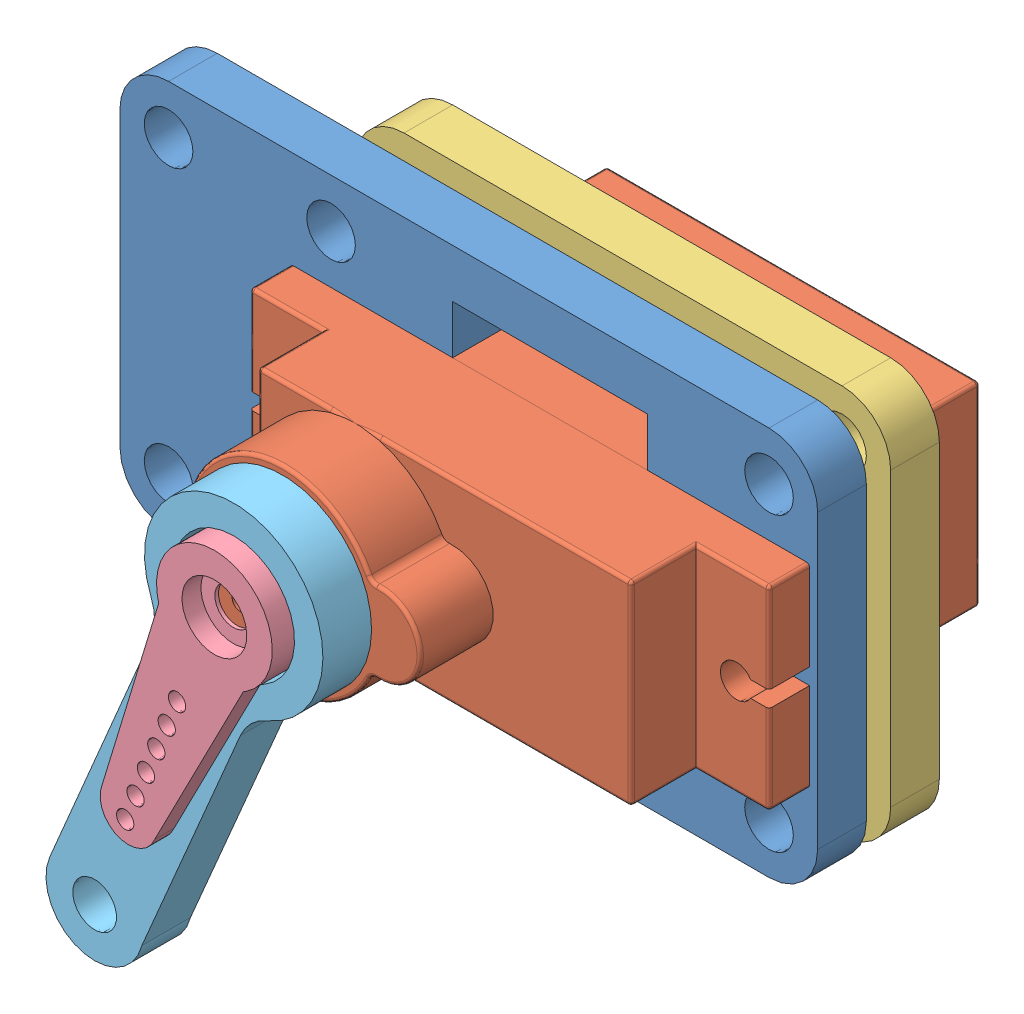
SolidWorks assembly Montagem2, configuration Valor predeterminado. Lengths in mm.
Overall size (43.02 37.14 30.2).
5 component instances, 5 part files, 10 mates.
Components (placement in the parent):
- 22-1: 22 [Défaut] at (-31.5156 48.4679 41.5162) size (43.02 24 3)
- Servo-1: Servo [Valor predeterminado] at (7.2328 7.1554 29.5162) x (1 0 0) z (0 -1 0) size (32 28.61 12)
- 21-1: 21 [Défaut] at (-21.7974 23.8068 37.0162) size (33 24 3)
- Helice-2: Helice [Default] at (18.3291 -0.913 62.5492) x (0.926593 -0.376065 0) z (0 0 1) size (7.14 19.41 4.19)
- 5-1: 5 [Défaut] at (-16.6615 -14.3676 55.5162) x (-0.390245 -0.920711 0) z (0 0 1) size (30.47 11 3)
Mates (geometry in assembly coordinates):
- Coincidente7: coincident anti-aligned: plane of 22-1 through (32.2328 10.1554 44.5162) normal (0 0 1); plane of Servo-1 through (7.2328 -4.8446 44.5162) normal (0 0 -1)
- Coincidente8: coincident anti-aligned: plane of 22-1 through (24.7328 7.1554 44.5162) normal (0 -1 0); plane of Servo-1 through (7.2328 7.1554 29.5162) normal (0 1 0)
- Concêntrico3: concentric aligned: circle of 22-1; circle of 21-1
- Concêntrico4: concentric aligned: circle of 22-1; circle of 21-1
- Coincidente11: coincident anti-aligned: plane of Servo-1 through (16.1182 -0.3402 55.5162) normal (0 0 1); plane of Helice-2 through (13.2328 1.1554 55.5162) normal (0 0 -1)
- Concêntrico5: concentric aligned: circle of Servo-1; circle of Helice-2
- Concêntrico6: concentric aligned: circle of Servo-1; circle of 5-1
- Coincidente12: coincident anti-aligned: plane of Servo-1 through (16.1182 -0.3402 55.5162) normal (0 0 1); plane of 5-1 through (4.659 -19.0729 55.5162) normal (0 0 -1)
- Coincidente13: coincident anti-aligned: plane of 22-1 through (30.2328 -4.8446 44.5162) normal (-1 0 0); plane of Servo-1 through (30.2328 -4.8446 29.5162) normal (1 0 0)
- Bloquear1: lock: unknown of Helice-2; unknown of 5-1
